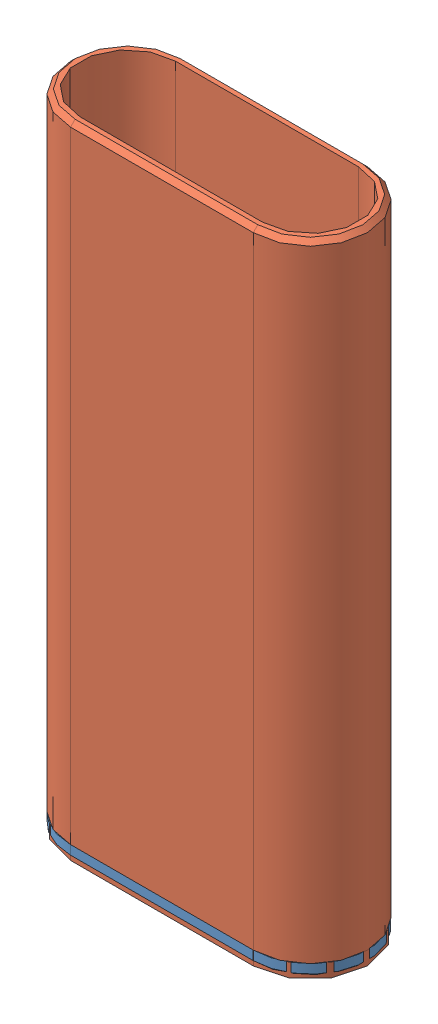
SolidWorks assembly Shell, configuration Default. Lengths in mm.
Overall size (65.05 140.17 25).
6 component instances, 4 part files, 14 mates.
Components (placement in the parent):
- Shell_Base-1: Shell_Base [Default] at origin size (65 15.6 25)
- Shell_Wall-1: Shell_Wall [Default] at (0.0511 0 0) size (65 140 25)
- 90710A030_TYPE 18-8 SS THIN HEX NUT - DIN 439B-1: 90710A030_TYPE 18-8 SS THIN HEX NUT - DIN 439B [90710A030] at (20.0511 2.3 0) x (0.866025 0 -0.5) z (0.5 0 0.866025) size (5.5 2.19 6.35)
- 90710A030_TYPE 18-8 SS THIN HEX NUT - DIN 439B-2: 90710A030_TYPE 18-8 SS THIN HEX NUT - DIN 439B [90710A030] at (-19.9489 2.3 0) x (0 0 -1) z (1 0 0) size (5.5 2.19 6.35)
- 92125A130_TYPE 18-8 SS FLAT-HEAD SOCKET CAP SCREW-1: 92125A130_TYPE 18-8 SS FLAT-HEAD SOCKET CAP SCREW [92125A130] at (20 -3.65 0) x (0.704365 0 0.709838) z (0 -1 0) size (6 6 10.3)
- 92125A130_TYPE 18-8 SS FLAT-HEAD SOCKET CAP SCREW-2: 92125A130_TYPE 18-8 SS FLAT-HEAD SOCKET CAP SCREW [92125A130] at (-19.9489 -3.65 0) x (-0.322578 0 -0.946543) z (0 -1 0) size (6 6 10.3)
Mates (geometry in assembly coordinates):
- Coincident1: coordinate: point of Shell_Base-1
- Coincident2: coincident anti-aligned: plane of Shell_Base-1 through (-20 -0.6 0) normal (0 1 0); plane of Shell_Wall-1 through (-19.9489 -0.6 0) normal (0 -1 0)
- Concentric1: concentric aligned: cylinder of Shell_Base-1 through (-19.9489 -3.6 0) axis (0 -1 0) radius 1.8; cylinder of Shell_Wall-1 through (-19.9489 -0.6 0) axis (0 -1 0) radius 1.8
- Coincident3: coincident aligned: plane of Shell_Base-1 through (-20 -3.6 12.5) normal (0 0 1); plane of Shell_Wall-1 through (-19.9489 136.4 12.5) normal (0 0 1)
- Concentric3: concentric aligned: circle of 90710A030_TYPE 18-8 SS THIN HEX NUT - DIN 439B-2; circle of Shell_Wall-1
- Parallel1: parallel aligned: plane of Shell_Wall-1 through (0.0511 4.4 -2.85) normal (0 0 1); plane of 90710A030_TYPE 18-8 SS THIN HEX NUT - DIN 439B-2 through (-21.5366 3.2 2.75) normal (0 0 1)
- Coincident6: coincident anti-aligned: plane of Shell_Wall-1 through (0.0511 1.4 0) normal (0 1 0); plane of 90710A030_TYPE 18-8 SS THIN HEX NUT - DIN 439B-2 through (-21.5366 1.4 2.75) normal (0 -1 0)
- Concentric4: concentric anti-aligned: circle of Shell_Wall-1; circle of 90710A030_TYPE 18-8 SS THIN HEX NUT - DIN 439B-1
- Parallel2: parallel aligned: plane of Shell_Wall-1 through (0.0511 4.4 -2.85) normal (0 0 1); plane of 90710A030_TYPE 18-8 SS THIN HEX NUT - DIN 439B-1 through (18.4634 3.2 2.75) normal (0 0 1)
- Coincident8: coincident anti-aligned: plane of Shell_Wall-1 through (0.0511 1.4 0) normal (0 1 0); plane of 90710A030_TYPE 18-8 SS THIN HEX NUT - DIN 439B-1 through (16.8757 1.4 0) normal (0 -1 0)
- Concentric5: concentric aligned: circle of Shell_Base-1; circle of 92125A130_TYPE 18-8 SS FLAT-HEAD SOCKET CAP SCREW-1
- Coincident9: coincident aligned: cone of Shell_Base-1 through (20 -3.6 0) axis (0 1 0); cone of 92125A130_TYPE 18-8 SS FLAT-HEAD SOCKET CAP SCREW-1 through (20 -1.95 0) axis (0 1 0)
- Concentric6: concentric aligned: circle of Shell_Base-1; circle of 92125A130_TYPE 18-8 SS FLAT-HEAD SOCKET CAP SCREW-2
- Coincident10: coincident aligned: cone of Shell_Base-1 through (-19.9489 -3.6 0) axis (0 1 0); cone of 92125A130_TYPE 18-8 SS FLAT-HEAD SOCKET CAP SCREW-2 through (-19.9489 -1.95 0) axis (0 1 0)
